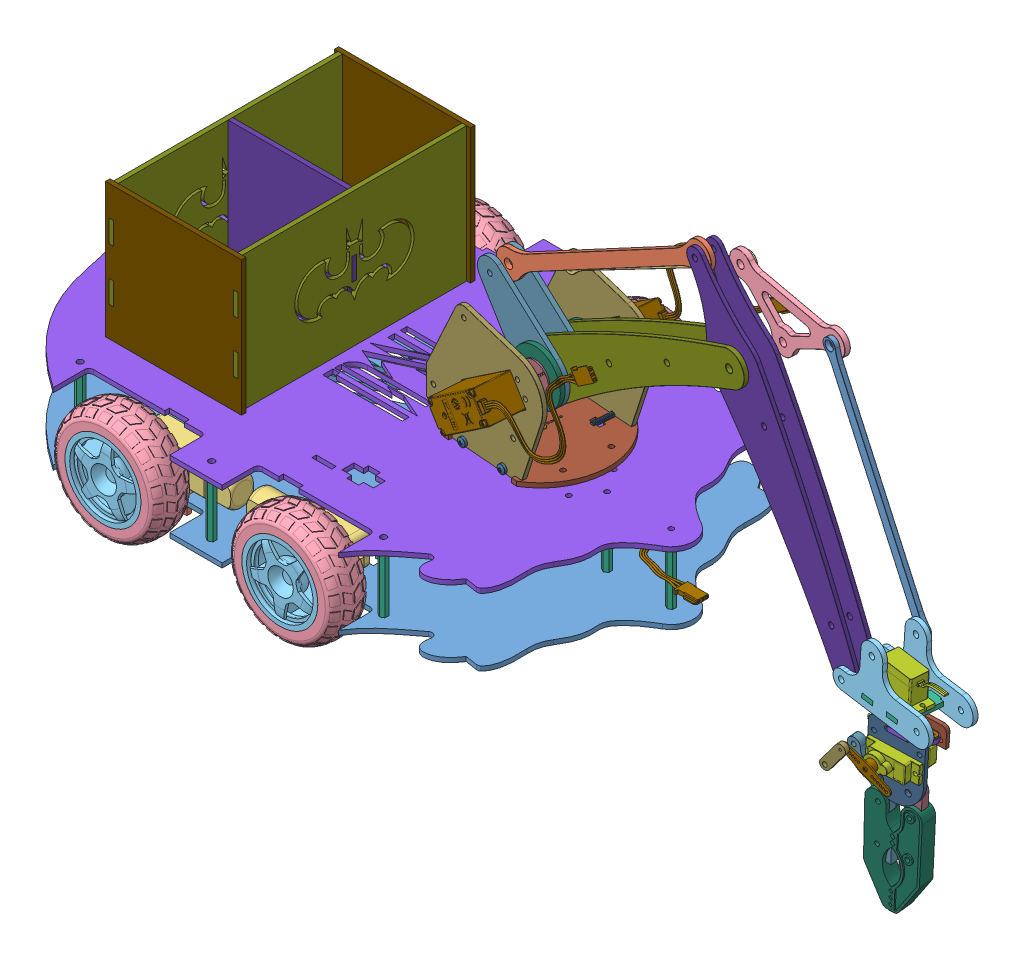
SolidWorks assembly Assem CAR, configuration Default. Lengths in mm.
Overall size (594.44 321.48 366.53).
90 component instances, 36 part files, 102 mates.
Components (placement in the parent):
- Car chassis botton-1: Car chassis botton [Default] at origin size (386.36 3 250)
- Motor Holder-1: Motor Holder [Default] at (-38.1 10 98) size (16 34 3)
- Motor Holder-2: Motor Holder [Default] at (-38.2 10 76) size (16 34 3)
- Motor Holder-3: Motor Holder [Default] at (38.1 10 98) size (16 34 3)
- Motor Holder-4: Motor Holder [Default] at (38.1 10 76) size (16 34 3)
- Motor Holder-5: Motor Holder [Default] at (38.2 10 -79) size (16 34 3)
- Motor Holder-6: Motor Holder [Default] at (38.1 10 -101) size (16 34 3)
- Motor Holder-7: Motor Holder [Default] at (-38.1 10 -79) size (16 34 3)
- Motor Holder-8: Motor Holder [Default] at (-38.1 10 -101) size (16 34 3)
- 6V 250rpm DC motor-2: 6V 250rpm DC motor [Default] at (37.6 14 79) x (0 -1 0) z (0 0 1) size (22 70.71 36.6)
- 6V 250rpm DC motor-3: 6V 250rpm DC motor [Default] at (-37.7 14 79) x (0 1 0) z (0 0 1) size (22 70.71 36.6)
- 6V 250rpm DC motor-4: 6V 250rpm DC motor [Default] at (-37.6 14 -98) x (0 1 0) z (0 0 1) size (22 70.71 36.6)
- 6V 250rpm DC motor-5: 6V 250rpm DC motor [Default] at (37.6 14 -79.4) x (0 1 0) z (0 0 -1) size (22 70.71 36.6)
- Wheel Assembly-2: Wheel Assembly [Default] at (59.1 14 -115.7) x (-0.862131 0.506685 0) z (0.506685 0.862131 0) size (74.1 30.08 74.05)
  - Tire-1: Tire [Default] at origin size (74.1 25.4 74.05)
  - Wheel Hub-1: Wheel Hub [Default] x (1 0 0) z (0 -1 0) size (50.8 50.8 30.08)
- Wheel Assembly-3: Wheel Assembly [Default] at (-59.1 14 -115.7) x (0.632687 0.774407 0) z (0.774407 -0.632687 0) size (74.1 30.08 74.05)
  - Tire-1: Tire [Default] at origin size (74.1 25.4 74.05)
  - Wheel Hub-1: Wheel Hub [Default] x (1 0 0) z (0 -1 0) size (50.8 50.8 30.08)
- Wheel Assembly-4: Wheel Assembly [Default] at (59.1 14 115.3) x (0.841276 0.540605 0) z (-0.540605 0.841276 0) size (74.1 30.08 74.05)
  - Tire-1: Tire [Default] at origin size (74.1 25.4 74.05)
  - Wheel Hub-1: Wheel Hub [Default] x (1 0 0) z (0 -1 0) size (50.8 50.8 30.08)
- Wheel Assembly-5: Wheel Assembly [Default] at (-59.2 14 115.3) x (-0.859592 -0.510981 0) z (0.510981 -0.859592 0) size (74.1 30.08 74.05)
  - Tire-1: Tire [Default] at origin size (74.1 25.4 74.05)
  - Wheel Hub-1: Wheel Hub [Default] x (1 0 0) z (0 -1 0) size (50.8 50.8 30.08)
- Hex pillar-1: Hex pillar [Default] at (192.8187 3 0) size (4.7 48.16 5.43)
- Hex pillar-2: Hex pillar [Default] at (101.5 3 -101) size (4.7 48.16 5.43)
- Hex pillar-3: Hex pillar [Default] at (0 3 -114.5) x (0.848929 0 0.528507) z (-0.528507 0 0.848929) size (4.7 48.16 5.43)
- Hex pillar-4: Hex pillar [Default] at (-101.5 3 -101) size (4.7 48.16 5.43)
- Hex pillar-5: Hex pillar [Default] at (-165 3 0) size (4.7 48.16 5.43)
- Hex pillar-6: Hex pillar [Default] at (-101.5 3 101) x (0.615835 0 0.787875) z (-0.787875 0 0.615835) size (4.7 48.16 5.43)
- Hex pillar-7: Hex pillar [Default] at (0 3 114.5) size (4.7 48.16 5.43)
- Hex pillar-8: Hex pillar [Default] at (101.5 3 101) x (0.529946 0 -0.848032) z (0.848032 0 0.529946) size (4.7 48.16 5.43)
- Hex pillar-9: Hex pillar [Default] at (150 3 0) x (0.999616 0 -0.027726) z (0.027726 0 0.999616) size (4.7 48.16 5.43)
- nut-1: nut [Default] at (38.1 22.5 -103) x (0 0 1) z (-0.255756 0.966741 0) size (32 4.5 4.5)
- nut-2: nut [Default] at (38.1 5.5 -103) x (0 0 1) z (-0.300884 0.953661 0) size (32 4.5 4.5)
- nut-3: nut [Default] at (-38.1 22.5 -103) x (0 0 1) z (-0.343086 0.939304 0) size (32 4.5 4.5)
- nut-4: nut [Default] at (-38.1 4 -103) x (0 0 1) z (0.435053 0.900405 0) size (32 4.5 4.5)
- nut-5: nut [Default] at (38.1 22.5 103) x (0 0 -1) z (0.847584 0.53066 0) size (32 4.5 4.5)
- nut-6: nut [Default] at (38.1 4 103) x (0 0 -1) z (0.998461 -0.05545 0) size (32 4.5 4.5)
- nut-7: nut [Default] at (-38.1 4 103) x (0 0 -1) z (0.356578 -0.934266 0) size (32 4.5 4.5)
- nut-8: nut [Default] at (-38.1 22.5 103) x (0 0 -1) z (0.499498 -0.866315 0) size (32 4.5 4.5)
- Car chassis top-1: Car chassis top [Default] at (0 45 0) size (386.36 3 250)
- Servo Futaba S3003.stp-1: Servo Futaba S3003.stp [Default] at (95.5 21.5 0) x (0 0 1) z (0 1 0) size (44.37 151.18 42.35)
- Assem Arms2-1: Assem Arms2 [Default] at (108.509 46.6114 19.366) x (0.557664 -0.010002 -0.830006) z (0.829816 -0.017839 0.557752) size (226.25 313.58 319.53)
  - pan head cross rece0ss screw_iso-20: pan head cross rece0ss screw_iso [ISO 7045 - M3 x 16 - Z - 16S] at (40.1963 16.3953 -44.7782) x (-0.87225 0 0.489061) z (-0.265849 -0.839351 -0.474146) size (18.35 5.6 5.6)
  - pan head cross rece0ss screw_iso-22: pan head cross rece0ss screw_iso [ISO 7045 - M3 x 16 - Z - 16S] at (54.3761 16.9884 -19.4883) x (-0.87225 0 0.489061) z (0.426844 0.488109 0.761284) size (18.35 5.6 5.6)
  - pan head cross rece0ss screw_iso-23: pan head cross rece0ss screw_iso [ISO 7045 - M3 x 16 - Z - 16S] at (-25.8377 16.3953 -7.7537) x (0.87225 0 -0.489061) z (0.489061 0 0.87225) size (18.35 5.6 5.6)
  - pan head cross rece0ss screw_iso-24: pan head cross rece0ss screw_iso [ISO 7045 - M3 x 16 - Z - 16S] at (-11.6579 16.9884 17.5363) x (0.87225 0 -0.489061) z (0.489061 0 0.87225) size (18.35 5.6 5.6)
  - Part9-1: Part9 [Default] at (14.258 13.6925 -13.5443) x (0.488959 0.020451 0.872067) z (-0.87225 0 0.489061) size (92 3 75)
  - Part1-1: Part1 [Default] at (42.6761 6.6939 -29.314) x (-0.488959 -0.020451 -0.872067) z (0.87225 0 -0.489061) size (84.94 80.79 3)
  - Part1-2: Part1 [Default] at (-16.5544 6.6939 3.8959) x (-0.488959 -0.020451 -0.872067) z (0.87225 0 -0.489061) size (84.94 80.79 3)
  - Servo Futaba S3003.stp-1: Servo Futaba S3003.stp [Default] at (-33.8607 55.5272 21.081) x (-0.288648 0.80725 -0.51481) z (0.87225 0 -0.489061) size (44.37 151.18 42.35)
  - Servo Futaba S3003.stp-2: Servo Futaba S3003.stp [Default] at (68.9822 55.5272 -36.5819) x (0.288648 -0.80725 0.51481) z (-0.87225 0 0.489061) size (44.37 151.18 42.35)
  - SERVO MOTOR Leaf-2: SERVO MOTOR Leaf [Default] at (7.5067 61.4293 7.1415) x (-0.341934 -0.71496 -0.609846) z (-0.349659 0.699165 -0.623624) size (20 5 20)
  - Part8-2: Part8 [Default] at (22.7419 116.7338 28.1796) x (-0.349659 0.699165 -0.623624) z (-0.87225 0 0.489061) size (80.5 35 3)
  - Part8-3: Part8 [Default] at (35.4815 116.7338 21.0367) x (-0.349659 0.699165 -0.623624) z (-0.87225 0 0.489061) size (80.5 35 3)
  - Waasher-3: Waasher [Default] at (10.1235 61.4293 5.6744) x (0.349659 -0.699165 0.623624) z (-0.87225 0 0.489061) size (35 35 3)
  - Waasher-4: Waasher [Default] at (32.8939 61.4293 -7.0928) x (0.115909 -0.971509 0.206726) z (0.87225 0 -0.489061) size (35 35 3)
  - Part2-3: Part2 [Default] at (6.2842 25.132 -48.4176) x (0.144187 -0.955551 0.257161) z (-0.87225 0 0.489061) size (60.81 172.93 3)
  - Part2-4: Part2 [Default] at (-8.5441 25.132 -40.1035) x (0.144187 -0.955551 0.257161) z (-0.87225 0 0.489061) size (60.81 172.93 3)
  - Part5-3: Part5 [Default] at (4.7495 30.3786 -51.1548) x (-0.343534 0.711748 -0.612699) z (0.87225 0 -0.489061) size (224.03 63.02 2.5)
  - Part5-4: Part5 [Default] at (-5.2814 30.3786 -45.5306) x (-0.343534 0.711748 -0.612699) z (0.87225 0 -0.489061) size (224.03 63.02 2.5)
  - SERVO MOTOR Leaf-3: SERVO MOTOR Leaf [Default] at (35.5107 61.4293 -8.56) x (-0.475127 -0.237003 -0.847398) z (0.115909 -0.971509 0.206726) size (20 5 20)
  - Part22-1: Part22 [Default] at (7.5987 61.4293 7.09) x (-0.352996 -0.692118 -0.629576) z (0.338488 -0.721784 0.6037) size (8.5 32 8.5)
  - part 6-2: part 6 [Default] at (11.9236 85.2607 -71.8932) x (-0.299121 0.79115 -0.533488) z (0.87225 0 -0.489061) size (153.11 32.4 3)
  - Part4-2: Part4 [Default] at (-30.3251 112.5374 -90.1964) x (0.161206 -0.944113 0.287514) z (-0.87225 0 0.489061) size (50.31 174.7 3)
  - Part 3-4: Part 3 [Default] at (-7.5406 76.9662 -113.7645) x (0.148401 -0.95285 0.264676) z (-0.87225 0 0.489061) size (42.48 154.39 2.5)
  - Part7-2: Part7 [Default] at (122.5992 -71.5202 125.4988) x (0.48636 -0.104953 0.867432) z (-0.87225 0 0.489061) size (84.81 40.3 3.5)
  - GPart 6-1: GPart 6 [Default] at (158.21 -6.5964 198.2127) x (0.488552 -0.045613 0.871342) z (-0.87225 0 0.489061) size (70 41 3)
  - GPart 6-2: GPart 6 [Default] at (134.3104 -6.5964 211.613) x (0.488552 -0.045613 0.871342) z (-0.87225 0 0.489061) size (70 41 3)
  - GPart 7-1: GPart 7 [Default] at (146.0278 -0.6255 205.9296) x (0.488552 -0.045613 0.871342) z (0.022308 0.998959 0.039786) size (31 29 3)
  - SERVO MOTOR Leaf-4: SERVO MOTOR Leaf [Default] at (14.258 13.6925 -13.5443) x (0.489204 0.020451 0.87193) z (0.872112 -0.000006 -0.489306) size (20 5 20)
  - Servo Motor-1: Servo Motor [Default] at (146.4851 19.8532 206.7452) x (0.488552 -0.045613 0.871342) z (0.87225 0 -0.489061) size (46.97 30.5 12)
  - GPart 8-1: GPart 8 [Default] at (148.4136 -14.3623 210.1849) x (0.633536 -0.044911 0.772409) z (0.022308 0.998959 0.039786) size (35 18 3)
  - SERVO MOTOR Leaf Straight-1: SERVO MOTOR Leaf Straight [Default] at (148.4471 -12.8639 210.2446) x (0.773392 0.007975 -0.633878) z (0.633536 -0.044911 0.772409) size (7.33 5 34.5)
  - GPart 4-1: GPart 4 [Default] at (141.1343 -29.4196 215.3123) x (0.633536 -0.044911 0.772409) z (0.773392 0.007975 -0.633878) size (35 45 2.5)
  - GPart 5-1: GPart 5 [Default] at (155.0554 -29.276 203.9025) x (-0.633536 0.044911 -0.772409) z (-0.773392 -0.007975 0.633878) size (35 13 2.5)
  - Servo Motor-2: Servo Motor [Default] at (153.8953 -29.288 204.8533) x (-0.633536 0.044911 -0.772409) z (0.022308 0.998959 0.039786) size (46.97 30.5 12)
  - SERVO MOTOR Leaf Straight-2: SERVO MOTOR Leaf Straight [Default] at (125.2756 -29.3002 221.2061) x (-0.296655 -0.879125 -0.373008) z (0.560233 -0.476524 0.677542) size (7.33 5 34.5)
  - GPart 9-1: GPart 9 [Default] at (112.9469 -28.7956 208.5366) x (-0.36315 -0.814017 -0.45332) z (0.773392 0.007975 -0.633878) size (22.5 6.5 3)
  - GPart 1-1: GPart 1 [Default] at (148.096 -45.7647 219.6565) x (0.773392 0.007975 -0.633878) z (0.633716 -0.035608 0.772746) size (5 59.63 16.16)
  - GPart 2-1: GPart 2 [Default] at (137.3258 -45.0013 206.5256) x (0.773392 0.007975 -0.633878) z (0.633928 -0.011396 0.773308) size (5 63.64 32.05)
  - GPart 3-1: GPart 3 [Default] at (144.4256 -59.8444 211.0572) x (-0.633716 0.035608 -0.772746) z (-0.773392 -0.007975 0.633878) size (17.75 66.5 10)
  - GPart 3-2: GPart 3 [Default] at (144.6133 -59.4872 211.2907) x (0.633928 -0.011396 0.773308) z (0.773392 0.007975 -0.633878) size (17.75 66.5 10)
- Part front-1: Part front [Default] at (-105 93 0) x (0 0 -1) z (1 0 0) size (156 93 3)
- Part front-2: Part front [Default] at (-19 93 0) x (0 0 1) z (-1 0 0) size (156 93 3)
- Part mid-1: Part mid [Default] at (-62 93 -1.5) size (86 90 3)
- Part side-3: Part side [Default] at (-62 93 75) size (91 93 3)
- Part side-4: Part side [Default] at (-62 93 -78) size (91 93 3)
Mates (geometry in assembly coordinates):
- Concentric1: concentric anti-aligned: cylinder of Car chassis botton-1 through (150 3 0) axis (0 -1 0) radius 1.65; cylinder of Hex pillar-9 through (150 -3 0) axis (0 1 0) radius 1.5
- Coincident1: coincident anti-aligned: plane of Car chassis botton-1 through (0 3 0) normal (0 1 0); plane of Hex pillar-9 through (150 3 0) normal (0 -1 0)
- Concentric2: concentric anti-aligned: cylinder of Car chassis botton-1 through (192.8187 3 0) axis (0 -1 0) radius 1.65; cylinder of Hex pillar-1 through (192.8187 -3 0) axis (0 1 0) radius 1.5
- Coincident2: coincident anti-aligned: plane of Car chassis botton-1 through (0 3 0) normal (0 1 0); plane of Hex pillar-1 through (192.8187 3 0) normal (0 -1 0)
- Concentric3: concentric anti-aligned: cylinder of Car chassis botton-1 through (101.5 3 -101) axis (0 -1 0) radius 2; cylinder of Hex pillar-2 through (101.5 -3 -101) axis (0 1 0) radius 1.5
- Coincident3: coincident anti-aligned: plane of Car chassis botton-1 through (0 3 0) normal (0 1 0); plane of Hex pillar-2 through (101.5 3 -101) normal (0 -1 0)
- Concentric4: concentric anti-aligned: cylinder of Car chassis botton-1 through (0 3 -114.5) axis (0 -1 0) radius 2; cylinder of Hex pillar-3 through (0 -3 -114.5) axis (0 1 0) radius 1.5
- Coincident4: coincident anti-aligned: plane of Car chassis botton-1 through (0 3 0) normal (0 1 0); plane of Hex pillar-3 through (0 3 -114.5) normal (0 -1 0)
- Concentric5: concentric anti-aligned: cylinder of Car chassis botton-1 through (-101.5 3 -101) axis (0 -1 0) radius 2; cylinder of Hex pillar-4 through (-101.5 -3 -101) axis (0 1 0) radius 1.5
- Coincident5: coincident anti-aligned: plane of Car chassis botton-1 through (0 3 0) normal (0 1 0); plane of Hex pillar-4 through (-101.5 3 -101) normal (0 -1 0)
- Concentric6: concentric anti-aligned: cylinder of Car chassis botton-1 through (-165 3 0) axis (0 -1 0) radius 1.65; cylinder of Hex pillar-5 through (-165 -3 0) axis (0 1 0) radius 1.5
- Coincident6: coincident anti-aligned: plane of Car chassis botton-1 through (0 3 0) normal (0 1 0); plane of Hex pillar-5 through (-165 3 0) normal (0 -1 0)
- Concentric7: concentric anti-aligned: cylinder of Car chassis botton-1 through (-101.5 3 101) axis (0 -1 0) radius 2; cylinder of Hex pillar-6 through (-101.5 -3 101) axis (0 1 0) radius 1.5
- Coincident7: coincident anti-aligned: plane of Car chassis botton-1 through (0 3 0) normal (0 1 0); plane of Hex pillar-6 through (-101.5 3 101) normal (0 -1 0)
- Concentric8: concentric anti-aligned: cylinder of Car chassis botton-1 through (0 3 114.5) axis (0 -1 0) radius 2; cylinder of Hex pillar-7 through (0 -3 114.5) axis (0 1 0) radius 1.5
- Coincident9: coincident anti-aligned: plane of Car chassis botton-1 through (0 3 0) normal (0 1 0); plane of Hex pillar-8 through (101.5 3 101) normal (0 -1 0)
- Concentric9: concentric anti-aligned: cylinder of Car chassis botton-1 through (101.5 3 101) axis (0 -1 0) radius 2; cylinder of Hex pillar-8 through (101.5 -3 101) axis (0 1 0) radius 1.5
- Coincident10: coincident anti-aligned: plane of Car chassis botton-1 through (0 3 98) normal (0 0 1); plane of Motor Holder-3 through (38.1 10 98) normal (0 0 -1)
- Coincident11: coincident anti-aligned: plane of Car chassis botton-1 through (31.5 3 0) normal (1 0 0); plane of Motor Holder-3 through (31.5 10 101) normal (-1 0 0)
- Coincident12: coincident anti-aligned: plane of Car chassis botton-1 through (0 0 0) normal (0 -1 0); plane of Motor Holder-3 through (38.1 0 101) normal (0 1 0)
- Coincident13: coincident anti-aligned: plane of Car chassis botton-1 through (0 3 79) normal (0 0 -1); plane of Motor Holder-4 through (38.1 10 79) normal (0 0 1)
- Coincident14: coincident anti-aligned: plane of Car chassis botton-1 through (31.5 3 0) normal (1 0 0); plane of Motor Holder-4 through (31.5 10 79) normal (-1 0 0)
- Coincident15: coincident anti-aligned: plane of Car chassis botton-1 through (0 0 0) normal (0 -1 0); plane of Motor Holder-4 through (38.1 0 79) normal (0 1 0)
- Coincident16: coincident anti-aligned: plane of Car chassis botton-1 through (0 3 79) normal (0 0 -1); plane of Motor Holder-2 through (-38.2 10 79) normal (0 0 1)
- Coincident17: coincident anti-aligned: plane of Car chassis botton-1 through (-44.8 3 0) normal (1 0 0); plane of Motor Holder-2 through (-44.8 10 79) normal (-1 0 0)
- Coincident18: coincident anti-aligned: plane of Car chassis botton-1 through (0 0 0) normal (0 -1 0); plane of Motor Holder-2 through (-38.2 0 79) normal (0 1 0)
- Coincident19: coincident anti-aligned: plane of Car chassis botton-1 through (0 3 98) normal (0 0 1); plane of Motor Holder-1 through (-38.1 10 98) normal (0 0 -1)
- Coincident20: coincident anti-aligned: plane of Car chassis botton-1 through (-31.5 3 0) normal (-1 0 0); plane of Motor Holder-1 through (-31.5 10 101) normal (1 0 0)
- Coincident21: coincident anti-aligned: plane of Car chassis botton-1 through (0 0 0) normal (0 -1 0); plane of Motor Holder-1 through (-38.1 0 101) normal (0 1 0)
- Coincident22: coincident anti-aligned: plane of Car chassis botton-1 through (0 3 -79) normal (0 0 1); plane of Motor Holder-7 through (-38.1 10 -79) normal (0 0 -1)
- Coincident23: coincident anti-aligned: plane of Car chassis botton-1 through (-31.5 3 0) normal (-1 0 0); plane of Motor Holder-7 through (-31.5 10 -76) normal (1 0 0)
- Coincident24: coincident anti-aligned: plane of Car chassis botton-1 through (0 0 0) normal (0 -1 0); plane of Motor Holder-7 through (-38.1 0 -76) normal (0 1 0)
- Coincident25: coincident anti-aligned: plane of Car chassis botton-1 through (0 3 -98) normal (0 0 -1); plane of Motor Holder-8 through (-38.1 10 -98) normal (0 0 1)
- Coincident26: coincident anti-aligned: plane of Car chassis botton-1 through (-31.5 3 0) normal (-1 0 0); plane of Motor Holder-8 through (-31.5 10 -98) normal (1 0 0)
- Coincident27: coincident anti-aligned: plane of Car chassis botton-1 through (0 0 0) normal (0 -1 0); plane of Motor Holder-8 through (-38.1 0 -98) normal (0 1 0)
- Coincident28: coincident anti-aligned: plane of Motor Holder-8 through (-38.1 10 -98) normal (0 0 1); plane of 6V 250rpm DC motor-4 through (-37.6 14 -98) normal (0 0 -1)
- Concentric10: concentric aligned: cylinder of Motor Holder-8 through (-38.1 22.5 -98) axis (0 0 -1) radius 1.75; cylinder of 6V 250rpm DC motor-4 through (-38.1 22.5 -70.4) axis (0 0 -1) radius 1.5
- Coincident30: coincident anti-aligned: plane of Car chassis botton-1 through (0 3 0) normal (0 1 0); plane of 6V 250rpm DC motor-4 through (-70.1 3 -79.4) normal (0 -1 0)
- Concentric11: concentric aligned: cylinder of Motor Holder-2 through (-38.2 22.5 79) axis (0 0 -1) radius 1.75; cylinder of 6V 250rpm DC motor-3 through (-38.2 22.5 106.6) axis (0 0 -1) radius 1.5
- Coincident31: coincident anti-aligned: plane of Motor Holder-2 through (-38.2 10 79) normal (0 0 1); plane of 6V 250rpm DC motor-3 through (-37.7 14 79) normal (0 0 -1)
- Coincident32: coincident anti-aligned: plane of Car chassis botton-1 through (0 3 0) normal (0 1 0); plane of 6V 250rpm DC motor-3 through (-70.2 3 97.6) normal (0 -1 0)
- Coincident33: coincident anti-aligned: plane of Motor Holder-4 through (38.1 10 79) normal (0 0 1); plane of 6V 250rpm DC motor-2 through (37.6 14 79) normal (0 0 -1)
- Concentric12: concentric aligned: cylinder of Motor Holder-4 through (38.1 22.5 79) axis (0 0 -1) radius 1.75; cylinder of 6V 250rpm DC motor-2 through (38.1 22.5 106.6) axis (0 0 -1) radius 1.5
- Coincident34: coincident anti-aligned: plane of Car chassis botton-1 through (0 3 0) normal (0 1 0); plane of 6V 250rpm DC motor-2 through (70.1 3 97.6) normal (0 -1 0)
- Coincident35: coincident anti-aligned: plane of Car chassis botton-1 through (0 3 -76) normal (0 0 -1); plane of Motor Holder-5 through (38.2 10 -76) normal (0 0 1)
- Coincident36: coincident anti-aligned: plane of Car chassis botton-1 through (44.8 3 0) normal (-1 0 0); plane of Motor Holder-5 through (44.8 10 -76) normal (1 0 0)
- Coincident37: coincident anti-aligned: plane of Car chassis botton-1 through (0 0 0) normal (0 -1 0); plane of Motor Holder-5 through (38.2 0 -76) normal (0 1 0)
- Coincident38: coincident anti-aligned: plane of Car chassis botton-1 through (31.5 3 0) normal (1 0 0); plane of Motor Holder-6 through (31.5 10 -98) normal (-1 0 0)
- Coincident39: coincident anti-aligned: plane of Car chassis botton-1 through (0 0 0) normal (0 -1 0); plane of Motor Holder-6 through (38.1 0 -98) normal (0 1 0)
- Coincident40: coincident anti-aligned: plane of Car chassis botton-1 through (0 3 -98) normal (0 0 -1); plane of Motor Holder-6 through (38.1 10 -98) normal (0 0 1)
- Coincident41: coincident anti-aligned: plane of Motor Holder-6 through (38.1 10 -98) normal (0 0 1); plane of 6V 250rpm DC motor-5 through (37.6 14 -98) normal (0 0 -1)
- Coincident42: coincident anti-aligned: plane of Car chassis botton-1 through (0 3 0) normal (0 1 0); plane of 6V 250rpm DC motor-5 through (70.1 3 -98) normal (0 -1 0)
- Concentric13: concentric anti-aligned: cylinder of Motor Holder-6 through (38.1 22.5 -98) axis (0 0 -1) radius 1.75; cylinder of 6V 250rpm DC motor-5 through (38.1 22.5 -107) axis (0 0 1) radius 1.5
- Concentric14: concentric anti-aligned: cylinder of 6V 250rpm DC motor-5 through (38.1 5.5 -107) axis (0 0 1) radius 1.5; cylinder of nut-2 through (38.1 5.5 -71) axis (0 0 -1) radius 1.5
- Coincident43: coincident anti-aligned: plane of Motor Holder-6 through (38.1 10 -101) normal (0 0 -1); plane of nut-2 through (38.1 5.5 -101) normal (0 0 1)
- Concentric15: concentric aligned: cylinder of Motor Holder-6 through (38.1 22.5 -98) axis (0 0 -1) radius 1.75; cylinder of nut-1 through (38.1 22.5 -71) axis (0 0 -1) radius 1.5
- Coincident44: coincident anti-aligned: plane of Motor Holder-6 through (38.1 10 -101) normal (0 0 -1); plane of nut-1 through (38.1 22.5 -101) normal (0 0 1)
- Concentric17: concentric anti-aligned: circle of Motor Holder-8; cylinder of nut-3 through (-38.1 22.5 -71) axis (0 0 -1) radius 1.5
- Coincident45: coincident anti-aligned: plane of Motor Holder-8 through (-38.1 10 -101) normal (0 0 -1); plane of nut-3 through (-38.1 22.5 -101) normal (0 0 1)
- Concentric18: concentric aligned: cylinder of Motor Holder-8 through (-38.1 4 -98) axis (0 0 -1) radius 1.75; cylinder of nut-4 through (-38.1 4 -71) axis (0 0 -1) radius 1.5
- Coincident46: coincident anti-aligned: plane of Motor Holder-8 through (-38.1 10 -101) normal (0 0 -1); plane of nut-4 through (-38.1 4 -101) normal (0 0 1)
- Concentric19: concentric anti-aligned: cylinder of Motor Holder-1 through (-38.1 22.5 101) axis (0 0 -1) radius 1.75; cylinder of nut-8 through (-38.1 22.5 71) axis (0 0 1) radius 1.5
- Coincident47: coincident anti-aligned: plane of Motor Holder-1 through (-38.1 10 101) normal (0 0 1); plane of nut-8 through (-38.1 22.5 101) normal (0 0 -1)
- Concentric20: concentric anti-aligned: cylinder of Motor Holder-1 through (-38.1 4 101) axis (0 0 -1) radius 1.75; cylinder of nut-7 through (-38.1 4 71) axis (0 0 1) radius 1.5
- Coincident49: coincident anti-aligned: plane of Motor Holder-1 through (-38.1 10 101) normal (0 0 1); plane of nut-7 through (-38.1 4 101) normal (0 0 -1)
- Concentric21: concentric anti-aligned: cylinder of Motor Holder-3 through (38.1 4 101) axis (0 0 -1) radius 1.75; cylinder of nut-6 through (38.1 4 71) axis (0 0 1) radius 1.5
- Coincident50: coincident anti-aligned: plane of Motor Holder-3 through (38.1 10 101) normal (0 0 1); plane of nut-6 through (38.1 4 101) normal (0 0 -1)
- Concentric22: concentric anti-aligned: cylinder of Motor Holder-3 through (38.1 22.5 101) axis (0 0 -1) radius 1.75; cylinder of nut-5 through (38.1 22.5 71) axis (0 0 1) radius 1.5
- Coincident51: coincident anti-aligned: plane of Motor Holder-3 through (38.1 10 101) normal (0 0 1); plane of nut-5 through (38.1 22.5 101) normal (0 0 -1)
- Concentric23: concentric anti-aligned: cylinder of 6V 250rpm DC motor-2 through (59.1 14 53.5047) axis (0 0 1) radius 2.65; cylinder of Wheel Assembly-4/Wheel Hub-1 through (59.1 14 98.6) axis (0 0 -1) radius 4.75
- Coincident52: coincident anti-aligned: plane of 6V 250rpm DC motor-2 through (37.6 14 98.6) normal (0 0 1); plane of Wheel Assembly-4/Wheel Hub-1 through (59.1 14 98.6) normal (0 0 -1)
- Concentric24: concentric anti-aligned: cylinder of 6V 250rpm DC motor-3 through (-59.2 14 53.5047) axis (0 0 1) radius 2.65; cylinder of Wheel Assembly-5/Wheel Hub-1 through (-59.2 14 98.6) axis (0 0 -1) radius 4.75
- Coincident53: coincident anti-aligned: plane of 6V 250rpm DC motor-3 through (-37.7 14 98.6) normal (0 0 1); plane of Wheel Assembly-5/Wheel Hub-1 through (-59.2 14 98.6) normal (0 0 -1)
- Concentric25: concentric aligned: cylinder of 6V 250rpm DC motor-4 through (-59.1 14 -123.4953) axis (0 0 1) radius 2.65; cylinder of Wheel Assembly-3/Wheel Hub-1 through (-59.1 14 -99) axis (0 0 1) radius 4.75
- Coincident54: coincident anti-aligned: plane of 6V 250rpm DC motor-4 through (-37.6 14 -99) normal (0 0 -1); plane of Wheel Assembly-3/Wheel Hub-1 through (-59.1 14 -99) normal (0 0 1)
- Concentric26: concentric anti-aligned: cylinder of 6V 250rpm DC motor-5 through (59.1 14 -53.9047) axis (0 0 -1) radius 2.65; cylinder of Wheel Assembly-2/Wheel Hub-1 through (59.1 14 -99) axis (0 0 1) radius 4.75
- Coincident55: coincident anti-aligned: plane of 6V 250rpm DC motor-5 through (37.6 14 -99) normal (0 0 -1); plane of Wheel Assembly-2/Wheel Hub-1 through (59.1 14 -99) normal (0 0 1)
- Concentric27: concentric anti-aligned: cylinder of Hex pillar-1 through (192.8187 45 0) axis (0 1 0) radius 1.25; cylinder of Car chassis top-1 through (192.8187 48 0) axis (0 -1 0) radius 1.65
- Coincident56: coincident anti-aligned: plane of Hex pillar-1 through (192.8187 45 0) normal (0 1 0); plane of Car chassis top-1 through (0 45 0) normal (0 -1 0)
- Concentric28: concentric anti-aligned: cylinder of Hex pillar-5 through (-165 45 0) axis (0 1 0) radius 1.25; cylinder of Car chassis top-1 through (-165 48 0) axis (0 -1 0) radius 1.65
- Concentric29: concentric anti-aligned: cylinder of Hex pillar-7 through (0 45 114.5) axis (0 1 0) radius 1.25; cylinder of Car chassis top-1 through (0 48 114.5) axis (0 -1 0) radius 2
- Concentric30: concentric anti-aligned: cylinder of Car chassis top-1 through (120 48 -5) axis (0 -1 0) radius 1.55; cylinder of Servo Futaba S3003.stp-1 through (120 50.05 -5) axis (0 1 0) radius 1.35
- Coincident57: coincident anti-aligned: plane of Car chassis top-1 through (0 48 0) normal (0 1 0); plane of Servo Futaba S3003.stp-1 through (123.2 48 0) normal (0 -1 0)
- Concentric31: concentric aligned: cylinder of Car chassis top-1 through (71 48 -5) axis (0 -1 0) radius 1.55; cylinder of Servo Futaba S3003.stp-1 through (71 50.05 -5) axis (0 -1 0) radius 1.35
- Concentric33: concentric aligned: cylinder of Servo Futaba S3003.stp-1 through (105.5 61.5 0) axis (0 1 0) radius 3; cylinder of Assem Arms2-1/SERVO MOTOR Leaf-4 through (105.5 55.4 0) axis (0 1 0) radius 2.5
- Coincident58: coincident aligned: plane of Servo Futaba S3003.stp-1 through (95.5 59.4 0) normal (0 1 0); circle of Assem Arms2-1/SERVO MOTOR Leaf-4
- Coincident59: coincident anti-aligned: plane of Car chassis top-1 through (-102 38 0) normal (-1 0 0); plane of Part front-1 through (-102 93 0) normal (1 0 0)
- Coincident60: coincident anti-aligned: plane of Car chassis top-1 through (0 38 -35) normal (0 0 -1); plane of Part front-1 through (-102 93 -35) normal (0 0 1)
- Coincident61: coincident aligned: plane of Car chassis top-1 through (0 45 0) normal (0 -1 0); plane of Part front-1 through (-102 45 0) normal (0 -1 0)
- Coincident62: coincident anti-aligned: plane of Car chassis top-1 through (-22 38 0) normal (1 0 0); plane of Part front-2 through (-22 93 0) normal (-1 0 0)
- Coincident63: coincident anti-aligned: plane of Car chassis top-1 through (0 38 -50) normal (0 0 1); plane of Part front-2 through (-22 93 -50) normal (0 0 -1)
- Coincident64: coincident aligned: plane of Car chassis top-1 through (0 45 0) normal (0 -1 0); plane of Part front-2 through (-22 45 0) normal (0 -1 0)
- Coincident73: coincident aligned: plane of Part front-1 through (-105 93 0) normal (-1 0 0); plane of Part mid-1 through (-105 93 1.5) normal (-1 0 0)
- Coincident74: coincident anti-aligned: plane of Part front-1 through (-112 100.5 1.5) normal (0 -1 0); plane of Part mid-1 through (-62 100.5 1.5) normal (0 1 0)
- Coincident75: coincident anti-aligned: plane of Part front-1 through (-112 100.5 -1.5) normal (0 0 1); plane of Part mid-1 through (-62 93 -1.5) normal (0 0 -1)
- Coincident76: coincident anti-aligned: plane of Part front-2 through (-19 93 0) normal (1 0 0); plane of Part side-3 through (-19 93 78) normal (-1 0 0)
- Coincident77: coincident aligned: plane of Part front-2 through (-22 93 78) normal (0 0 1); plane of Part side-3 through (-62 93 78) normal (0 0 1)
- Coincident78: coincident anti-aligned: plane of Part front-2 through (-22 83 0) normal (0 1 0); plane of Part side-3 through (-62 83 78) normal (0 -1 0)
- Coincident79: coincident anti-aligned: plane of Part front-2 through (-19 93 0) normal (1 0 0); plane of Part side-4 through (-19 93 -75) normal (-1 0 0)
- Coincident80: coincident anti-aligned: plane of Part front-2 through (-22 93 0) normal (-1 0 0); plane of Part side-4 through (-22 93 -75) normal (1 0 0)
- Coincident81: coincident aligned: plane of Part front-2 through (-22 93 -78) normal (0 0 -1); plane of Part side-4 through (-62 93 -78) normal (0 0 -1)
- Coincident82: coincident anti-aligned: plane of Part front-2 through (-22 83 0) normal (0 1 0); plane of Part side-4 through (-62 83 -75) normal (0 -1 0)
